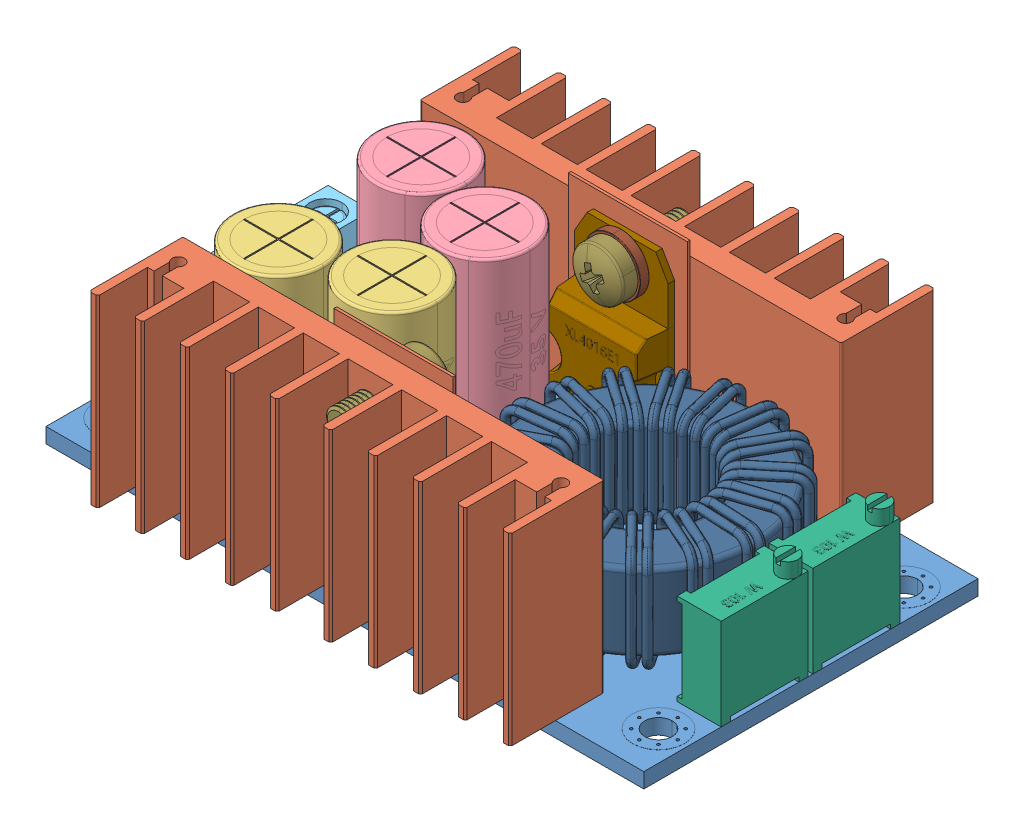
SolidWorks assembly XL4016E1 8A Buck Converter.STEP, configuration Default. Lengths in mm.
Overall size (65.3 28.6 46.4).
75 component instances, 21 part files, 0 mates.
Components (placement in the parent):
- 8A Buck Converter PCB.STEP-1: 8A Buck Converter PCB.STEP [Default] at origin size (65.3 1.67 36.5)
- Heat Exchanger.STEP-1: Heat Exchanger.STEP [Default] at (0 1.65 23.2) size (46 25.1 10.55)
- Heat Exchanger.STEP-2: Heat Exchanger.STEP [Default] at (0 1.65 -23.2) x (-1 0 0) z (0 0 -1) size (46 25.1 10.55)
- LargeGreen1000uF 35V Electrolytic Capacitor.STEP-1: LargeGreen1000uF 35V Electrolytic Capacitor.STEP [Default] at (-17.6782 1.65 7.8366) x (0 0 -1) z (1 0 0) size (9.9 26.01 9.9)
- LargeGreen1000uF 35V Electrolytic Capacitor.STEP-2: LargeGreen1000uF 35V Electrolytic Capacitor.STEP [Default] at (-8.0317 1.65 5.0694) x (0 0 -1) z (1 0 0) size (9.9 26.01 9.9)
- LargeGreen470uF 35V Electrolytic Capacitor.STEP-1: LargeGreen470uF 35V Electrolytic Capacitor.STEP [Default] at (-17.6617 1.65 -7.7514) x (0 0 1) z (-1 0 0) size (9.9 26.01 9.9)
- LargeGreen470uF 35V Electrolytic Capacitor.STEP-2: LargeGreen470uF 35V Electrolytic Capacitor.STEP [Default] at (-7.9869 1.65 -5.0151) x (0 0 1) z (-1 0 0) size (9.9 26.01 9.9)
- Screw Terminal x2.STEP-1: Screw Terminal x2.STEP [Default] at (-9.5 0 12.7839) x (-1 0 0) z (0 0 -1) size (7.95 12.9 10)
- Screw Terminal x2.STEP-2: Screw Terminal x2.STEP [Default] at (-9.5 0 2.7839) x (-1 0 0) z (0 0 -1) size (7.95 12.9 10)
- TrimmerW103.STEP-1: TrimmerW103.STEP [Default] at (32.65 6.9 -4.9563) x (0 0 1) z (-1 0 0) size (9.5 15.15 4.8)
- TrimmerW103.STEP-2: TrimmerW103.STEP [Default] at (32.65 6.9 5.0581) x (0 0 1) z (-1 0 0) size (9.5 15.15 4.8)
- whiteLEDShortLeed.STEP-1: whiteLEDShortLeed.STEP [Default] at (-13.9989 2.65 -0.1564) x (-1 0 0) z (0 0 -1) size (3.4 13.35 3.4)
- Schottky Diode 20A 45V STPS2045CT.STEP-1: Schottky Diode 20A 45V STPS2045CT.STEP [Default] at (-0.0419 13.7002 12.65) x (-0.999962 0.008727 0) z (-0.008727 -0.999962 0) size (10.22 3.95 22.6)
- XL4016E1 8A Voltage Regulator.STEP-1: XL4016E1 8A Voltage Regulator.STEP [Default] at (0 13.7 -12.65) x (1 0 0) z (0 -1 0) size (10.22 3.95 22.6)
- Coil for Convertor.STEP-1: Coil for Convertor.STEP [Default] at (14.3115 2.9157 0.0112) size (27.99 14.39 26.86)
- Small Plastic Washer.STEP-1: Small Plastic Washer.STEP [Default] at (0 18.5 -11.95) x (1 0 0) z (0 -1 0) size (6.1 1 6.1)
- Small Plastic Washer.STEP-2: Small Plastic Washer.STEP [Default] at (0 18.5 10.95) x (1 0 0) z (0 -1 0) size (6.1 1 6.1)
- pan head cross recess screw_iso_ISO 7045 - M3 x 8 - Z - 8S.STEP-1: pan head cross recess screw_iso_ISO 7045 - M3 x 8 - Z - 8S.STEP [Default] at (0 18.5 -8.55) x (0 0 -1) z (0.923728 0.383049 0) size (10.36 5.6 5.6)
- pan head cross recess screw_iso_ISO 7045 - M3 x 8 - Z - 8S.STEP-2: pan head cross recess screw_iso_ISO 7045 - M3 x 8 - Z - 8S.STEP [Default] at (0 18.5 8.55) x (0 0 1) z (-1 0 0) size (10.36 5.6 5.6)
- 1.7mmSmdCeramicCapacitorbrown.STEP-1: 1.7mmSmdCeramicCapacitorbrown.STEP [Default] at (2.849 0.0574 -8.3522) x (-1 0 0) z (0 0 1) size (2.02 0.49 1.04)
- smdChip8pin.STEP-1: smdChip8pin.STEP [Default] at (19.9049 -0.725 7.6791) x (1 0 0) z (0 0 -1) size (7.3 1.22 4.5)
- tinyVoltageRegulator.STEP-1: tinyVoltageRegulator.STEP [Default] at (13.3487 0 4.1964) x (-1 0 0) z (0 0 1) size (2.75 0.7 2.1)
- tinyVoltageRegulator.STEP-2: tinyVoltageRegulator.STEP [Default] at (20.3011 0 11.2685) x (0.999962 0 0.008727) z (0.008727 0 -0.999962) size (2.75 0.7 2.1)
- TinyVoltageRegulatorAMS1112.STEP-1: TinyVoltageRegulatorAMS1112.STEP [Default] at (15.0739 0.203 -4.8321) x (0 0 -1) z (-1 0 0) size (4.07 1.22 4.96)
- tinySMDResistor222.STEP-1: tinySMDResistor222.STEP [Default] at (21.8501 0.1177 -6.1765) x (0 0 -1) z (-1 0 0) size (1.52 0.38 0.79)
- tinySMDResistor.STEP-1: tinySMDResistor.STEP [Default] at (19.9225 0.1177 -6.1853) x (0 0 -1) z (-1 0 0) size (1.52 0.37 0.79)
- 1.7mmSmdCeramicCapacitorbrown.STEP-2: 1.7mmSmdCeramicCapacitorbrown.STEP [Default] at (24.1073 0.0574 -6.3061) x (0 0 -1) z (-1 0 0) size (2.02 0.49 1.04)
- 1.7mmSmdCeramicCapacitorbrown.STEP-3: 1.7mmSmdCeramicCapacitorbrown.STEP [Default] at (16.3262 0.0574 0.9562) x (0 0 -1) z (-1 0 0) size (2.02 0.49 1.04)
- 1.7mmSmdCeramicCapacitorbrown.STEP-4: 1.7mmSmdCeramicCapacitorbrown.STEP [Default] at (18.1093 0.0574 0.9562) x (0 0 -1) z (-1 0 0) size (2.02 0.49 1.04)
- tinySMDResistor.STEP-2: tinySMDResistor.STEP [Default] at (19.9874 0.1177 1.1419) x (0 0 -1) z (-1 0 0) size (1.52 0.37 0.79)
- tinySMDResistor.STEP-3: tinySMDResistor.STEP [Default] at (21.6733 0.1177 1.1419) x (0 0 -1) z (-1 0 0) size (1.52 0.37 0.79)
- tinySMDResistor.STEP-4: tinySMDResistor.STEP [Default] at (23.3916 0.1177 1.1419) x (0 0 -1) z (-1 0 0) size (1.52 0.37 0.79)
- 1.7mmSmdCeramicCapacitorbrown.STEP-5: 1.7mmSmdCeramicCapacitorbrown.STEP [Default] at (25.4211 0.0574 4.0139) x (0 0 -1) z (-1 0 0) size (2.02 0.49 1.04)
- 1.7mmSmdCeramicCapacitorbrown.STEP-6: 1.7mmSmdCeramicCapacitorbrown.STEP [Default] at (27.3088 0.0574 4.0139) x (0 0 -1) z (-1 0 0) size (2.02 0.49 1.04)
- 1.7mmSmdCeramicCapacitorbrown.STEP-7: 1.7mmSmdCeramicCapacitorbrown.STEP [Default] at (23.1777 0.0574 11.1322) x (0 0 -1) z (-1 0 0) size (2.02 0.49 1.04)
- 1.7mmSmdCeramicCapacitorbrown.STEP-8: 1.7mmSmdCeramicCapacitorbrown.STEP [Default] at (20.6839 0.0574 9.112) x (-0.999962 0 -0.008727) z (-0.008727 0 0.999962) size (2.02 0.49 1.04)
- tinySMDResistor.STEP-5: tinySMDResistor.STEP [Default] at (17.7351 0.1177 11.3427) x (0 0 -1) z (-1 0 0) size (1.52 0.37 0.79)
- tinySMDResistor.STEP-6: tinySMDResistor.STEP [Default] at (16.0827 0.1177 11.3427) x (0 0 -1) z (-1 0 0) size (1.52 0.37 0.79)
- tinySMDResistor.STEP-7: tinySMDResistor.STEP [Default] at (16.906 0.1177 9.0199) x (-0.999962 0 -0.008727) z (-0.008727 0 0.999962) size (1.52 0.37 0.79)
- tinySMDResistor.STEP-8: tinySMDResistor.STEP [Default] at (25.3907 0.1177 9.8144) x (-0.999962 0 -0.008727) z (-0.008727 0 0.999962) size (1.52 0.37 0.79)
- R010 Resistor SMD.STEP-1: R010 Resistor SMD.STEP [Default] at (-19.919 0 5.2469) x (0 0 -1) z (-1 0 0) size (6.7 0.52 3.1)
- solder.STEP-1: solder.STEP [Default] at (-27.65 0 -7.4411) x (-0.837169 0 -0.546944) z (-0.546944 0 0.837169) size (1.17 0.65 1.17)
- solder.STEP-2: solder.STEP [Default] at (-27.65 0 -2.711) x (-0.837169 0 -0.546944) z (-0.546944 0 0.837169) size (1.17 0.65 1.17)
- solder.STEP-3: solder.STEP [Default] at (-27.65 0 2.537) x (-0.837169 0 -0.546944) z (-0.546944 0 0.837169) size (1.17 0.65 1.17)
- solder.STEP-4: solder.STEP [Default] at (-27.65 0 7.3016) x (-0.837169 0 -0.546944) z (-0.546944 0 0.837169) size (1.17 0.65 1.17)
- solder1.8.STEP-1: solder1.8.STEP [Default] at (-20.8987 0 -15.5519) x (-0.837169 0 -0.546944) z (-0.546944 0 0.837169) size (1.8 0.65 1.8)
- solder1.8.STEP-2: solder1.8.STEP [Default] at (20.8325 0 -15.5519) x (-0.837169 0 -0.546944) z (-0.546944 0 0.837169) size (1.8 0.65 1.8)
- solder1.8.STEP-3: solder1.8.STEP [Default] at (20.8325 0 15.5391) x (-0.837169 0 -0.546944) z (-0.546944 0 0.837169) size (1.8 0.65 1.8)
- solder1.8.STEP-4: solder1.8.STEP [Default] at (-20.8987 0 15.5391) x (-0.837169 0 -0.546944) z (-0.546944 0 0.837169) size (1.8 0.65 1.8)
- solder.STEP-5: solder.STEP [Default] at (30.4698 0 7.6228) x (-0.837169 0 -0.546944) z (-0.546944 0 0.837169) size (1.17 0.65 1.17)
- solder.STEP-6: solder.STEP [Default] at (30.4698 0 2.537) x (-0.837169 0 -0.546944) z (-0.546944 0 0.837169) size (1.17 0.65 1.17)
- solder.STEP-7: solder.STEP [Default] at (30.4698 0 -2.454) x (-0.837169 0 -0.546944) z (-0.546944 0 0.837169) size (1.17 0.65 1.17)
- solder.STEP-8: solder.STEP [Default] at (30.4698 0 -7.4732) x (-0.837169 0 -0.546944) z (-0.546944 0 0.837169) size (1.17 0.65 1.17)
- solder.STEP-9: solder.STEP [Default] at (30.4698 0 -4.9355) x (-0.837169 0 -0.546944) z (-0.546944 0 0.837169) size (1.17 0.65 1.17)
- solder.STEP-10: solder.STEP [Default] at (30.4698 0 5.0529) x (-0.837169 0 -0.546944) z (-0.546944 0 0.837169) size (1.17 0.65 1.17)
- solder1.8.STEP-5: solder1.8.STEP [Default] at (1.0959 0 2.1506) x (-0.837169 0 -0.546944) z (-0.546944 0 0.837169) size (1.8 0.65 1.8)
- solder1.8.STEP-6: solder1.8.STEP [Default] at (8.9457 0 2.3519) x (-0.837169 0 -0.546944) z (-0.546944 0 0.837169) size (1.8 0.65 1.8)
- solder.STEP-11: solder.STEP [Default] at (-3.9931 0 -10.2017) x (-0.837169 0 -0.546944) z (-0.546944 0 0.837169) size (1.17 0.65 1.17)
- solder.STEP-12: solder.STEP [Default] at (-1.9931 0 -10.2017) x (-0.837169 0 -0.546944) z (-0.546944 0 0.837169) size (1.17 0.65 1.17)
- solder.STEP-13: solder.STEP [Default] at (0.0069 0 -10.2017) x (-0.837169 0 -0.546944) z (-0.546944 0 0.837169) size (1.17 0.65 1.17)
- solder.STEP-14: solder.STEP [Default] at (2.0069 0 -10.2017) x (-0.837169 0 -0.546944) z (-0.546944 0 0.837169) size (1.17 0.65 1.17)
- solder.STEP-15: solder.STEP [Default] at (4.0069 0 -10.2017) x (-0.837169 0 -0.546944) z (-0.546944 0 0.837169) size (1.17 0.65 1.17)
- solder.STEP-16: solder.STEP [Default] at (-2.7433 0 10.0764) x (-0.873283 0 -0.487214) z (-0.487214 0 0.873283) size (1.17 0.65 1.17)
- solder.STEP-17: solder.STEP [Default] at (-0.2033 0 10.0764) x (-0.873283 0 -0.487214) z (-0.487214 0 0.873283) size (1.17 0.65 1.17)
- solder.STEP-18: solder.STEP [Default] at (2.3367 0 10.0764) x (-0.873283 0 -0.487214) z (-0.487214 0 0.873283) size (1.17 0.65 1.17)
- solder.STEP-19: solder.STEP [Default] at (-8.0296 0 7.8897) x (-0.873283 0 -0.487214) z (-0.487214 0 0.873283) size (1.17 0.65 1.17)
- solder.STEP-20: solder.STEP [Default] at (-8.0296 0 2.259) x (-0.873283 0 -0.487214) z (-0.487214 0 0.873283) size (1.17 0.65 1.17)
- solder.STEP-21: solder.STEP [Default] at (-8.0296 0 -2.2341) x (-0.873283 0 -0.487214) z (-0.487214 0 0.873283) size (1.17 0.65 1.17)
- solder.STEP-22: solder.STEP [Default] at (-8.0296 0 -7.8634) x (-0.873283 0 -0.487214) z (-0.487214 0 0.873283) size (1.17 0.65 1.17)
- solder.STEP-23: solder.STEP [Default] at (-17.6872 0 -10.549) x (-0.873283 0 -0.487214) z (-0.487214 0 0.873283) size (1.17 0.65 1.17)
- solder.STEP-24: solder.STEP [Default] at (-17.6872 0 -4.9388) x (-0.873283 0 -0.487214) z (-0.487214 0 0.873283) size (1.17 0.65 1.17)
- solder.STEP-25: solder.STEP [Default] at (-17.6872 0 10.6333) x (-0.873283 0 -0.487214) z (-0.487214 0 0.873283) size (1.17 0.65 1.17)
- solder.STEP-26: solder.STEP [Default] at (-17.6872 0 5.0231) x (-0.873283 0 -0.487214) z (-0.487214 0 0.873283) size (1.17 0.65 1.17)
- solder.STEP-27: solder.STEP [Default] at (-15.2798 0 -0.193) x (-0.873283 0 -0.487214) z (-0.487214 0 0.873283) size (1.17 0.65 1.17)
- solder.STEP-28: solder.STEP [Default] at (-12.7921 0 -0.193) x (-0.873283 0 -0.487214) z (-0.487214 0 0.873283) size (1.17 0.65 1.17)
